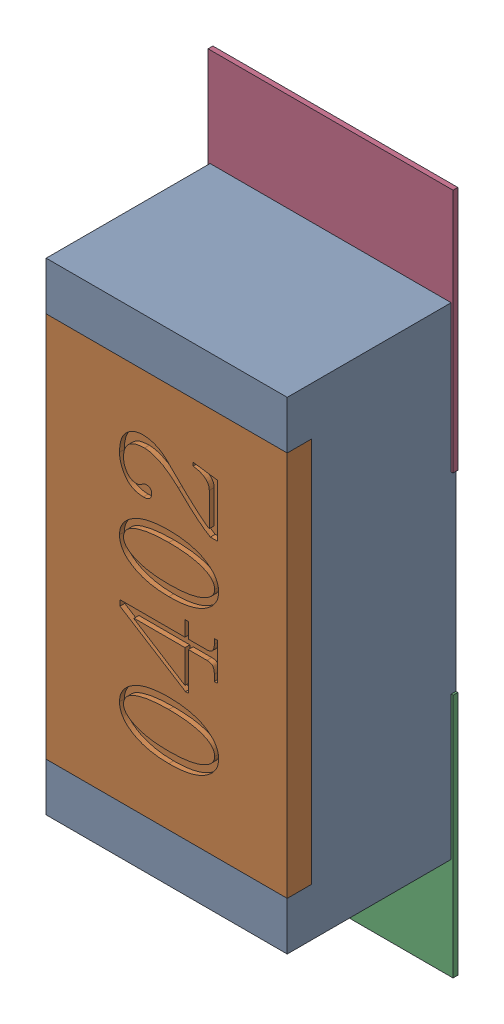
SolidWorks assembly R21, configuration Défaut. Lengths in mm.
Overall size (0.51 1.42 0.35).
5 component instances, 2 part files, 0 mates.
Components (placement in the parent):
- R0402-1: R0402 [Défaut] at (47.1425 -10.122 0) x (0 1 0) z (0 0 1) size (1 0.5 0.35)
- 6504207776-1: 6504207776 [Défaut] at (47.1423 -10.5791 0) size (0.51 0.51 0.01)
  - Extruded-1: Extruded [Défaut] at origin size (0.51 0.51 0.01)
- 6504207776-2: 6504207776 [Défaut] at (47.1423 -9.672 0) size (0.51 0.51 0.01)
  - Extruded-1: Extruded [Défaut] at origin size (0.51 0.51 0.01)
